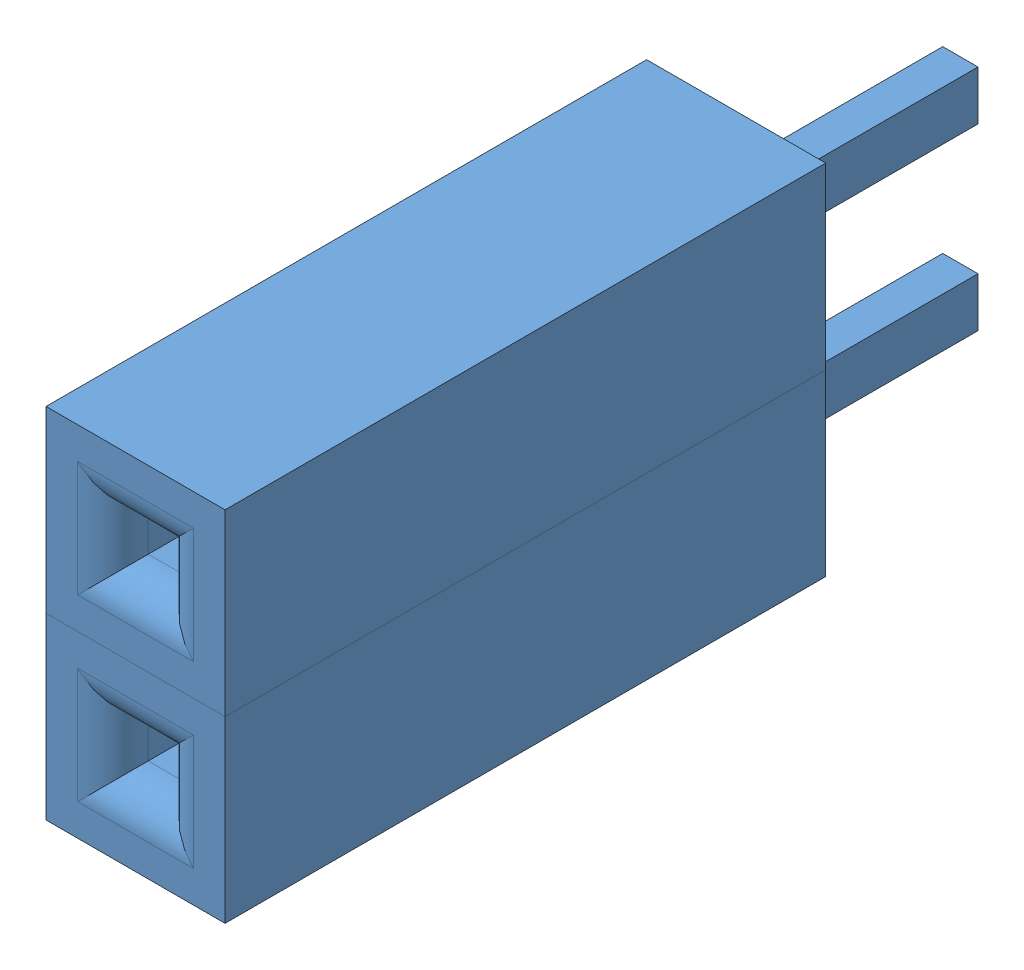
SolidWorks assembly Assem1, configuration Default. Lengths in mm.
Overall size (2.54 5.08 11.7).
2 component instances, 1 part files, 0 mates.
Components (placement in the parent):
- Female Header Pin-1: Female Header Pin [Default] at (-75.0213 18.8218 24.1304) size (2.54 2.54 11.7)
- Female Header Pin-2: Female Header Pin [Default] at (-75.0213 21.3618 24.1304) size (2.54 2.54 11.7)
